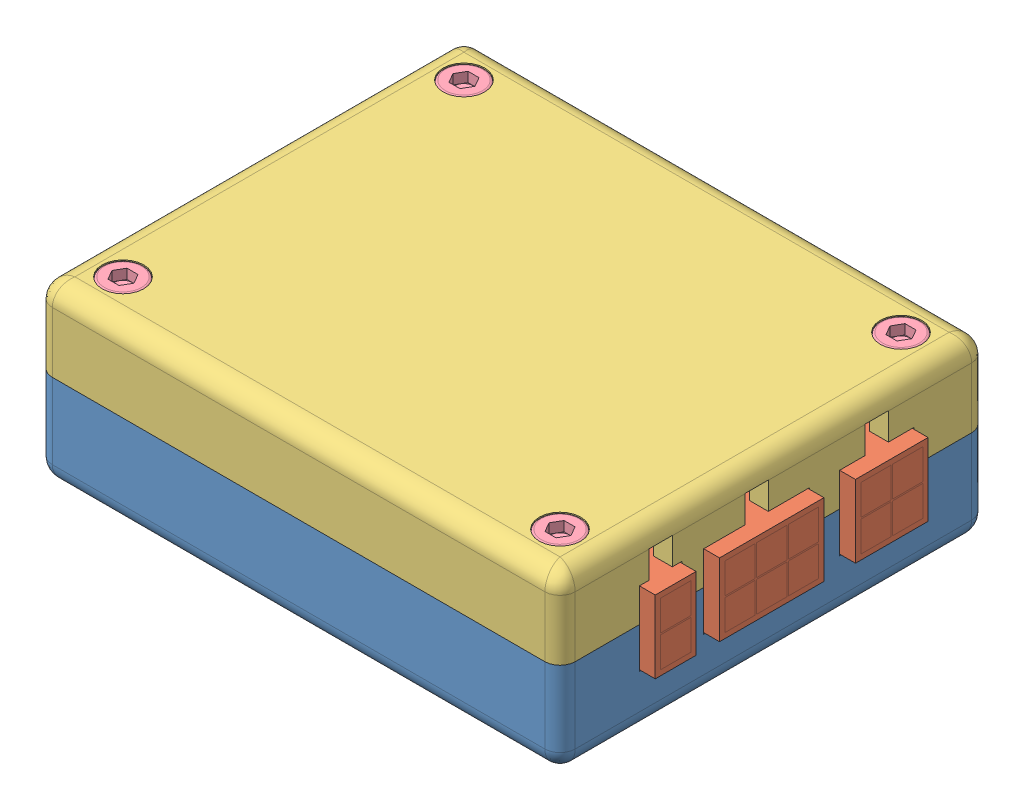
SolidWorks assembly Housing, configuration Standard. Lengths in mm.
Overall size (73.14 23 56.44).
11 component instances, 5 part files, 29 mates.
Components (placement in the parent):
- Housing-Bottom-1: Housing-Bottom [Standard] at (-69.135 0 56.435) size (69.14 12.5 56.44)
- Audio-Switch-1: Audio-Switch [Standard] at (-66.635 6.3 53.935) x (1 0 0) z (0 1 0) size (73.14 51.44 13.69)
- Housing-Top-1: Housing-Top [Standard] at (-69.135 20.5 56.435) size (69.14 15.9 56.44)
- socket head cap screw_din-1: socket head cap screw_din [DIN 912 M3 x 20 --- 20S] at (-5.675 23 50.76) x (0 -1 0) z (0 0 1) size (23 5.5 5.5)
- socket head cap screw_din-2: socket head cap screw_din [DIN 912 M3 x 20 --- 20S] at (-63.46 23 5.675) x (0 -1 0) z (0 0 1) size (23 5.5 5.5)
- socket head cap screw_din-3: socket head cap screw_din [DIN 912 M3 x 20 --- 20S] at (-63.46 23 50.76) x (0 -1 0) z (0 0 1) size (23 5.5 5.5)
- socket head cap screw_din-4: socket head cap screw_din [DIN 912 M3 x 20 --- 20S] at (-5.675 23 5.675) x (0 -1 0) z (0 0 1) size (23 5.5 5.5)
- hex thin nut chamfered gradeab_din-1: hex thin nut chamfered gradeab_din [Hexagon Thin Nut ISO 4035 - M3 - S] at (-63.46 2 50.76) x (1 0 0) z (0 1 0) size (5.5 6.35 1.8)
- hex thin nut chamfered gradeab_din-2: hex thin nut chamfered gradeab_din [Hexagon Thin Nut ISO 4035 - M3 - S] at (-63.46 2 5.675) x (1 0 0) z (0 1 0) size (5.5 6.35 1.8)
- hex thin nut chamfered gradeab_din-3: hex thin nut chamfered gradeab_din [Hexagon Thin Nut ISO 4035 - M3 - S] at (-5.675 2 5.675) x (1 0 0) z (0 1 0) size (5.5 6.35 1.8)
- hex thin nut chamfered gradeab_din-4: hex thin nut chamfered gradeab_din [Hexagon Thin Nut ISO 4035 - M3 - S] at (-5.675 2 50.76) x (1 0 0) z (0 1 0) size (5.5 6.35 1.8)
Mates (geometry in assembly coordinates):
- Deckungsgleich2: coincident anti-aligned: plane of Housing-Bottom-1 through (-66.635 12.5 53.935) normal (0 0 -1); plane of Audio-Switch-1 through (-2.5 5.5 53.935) normal (0 0 1)
- Deckungsgleich3: coincident anti-aligned: plane of Housing-Bottom-1 through (-66.635 12.5 53.935) normal (1 0 0); plane of Audio-Switch-1 through (-66.635 5.5 53.935) normal (-1 0 0)
- Deckungsgleich4: coincident anti-aligned: plane of Housing-Bottom-1 through (-63.46 5.5 50.76) normal (0 1 0); plane of Audio-Switch-1 through (-66.635 5.5 53.935) normal (0 -1 0)
- Deckungsgleich5: coincident anti-aligned: plane of Housing-Bottom-1 through (-67.135 12.5 2) normal (0 1 0); plane of Housing-Top-1 through (-69.135 12.5 56.435) normal (0 -1 0)
- Deckungsgleich6: coincident aligned: plane of Housing-Bottom-1 through (-69.135 2.5 54.435) normal (-1 0 0); plane of Housing-Top-1 through (-69.135 23 54.435) normal (-1 0 0)
- Deckungsgleich7: coincident aligned: plane of Housing-Bottom-1 through (-67.135 2.5 56.435) normal (0 0 1); plane of Housing-Top-1 through (-67.135 23 56.435) normal (0 0 1)
- Deckungsgleich8: coincident anti-aligned: plane of Housing-Top-1 through (-63.46 20 5.675) normal (0 1 0); plane of socket head cap screw_din-2 through (-60.71 20 5.675) normal (0 -1 0)
- Deckungsgleich9: coincident anti-aligned: plane of Housing-Top-1 through (-63.46 20 50.76) normal (0 1 0); plane of socket head cap screw_din-3 through (-60.71 20 50.76) normal (0 -1 0)
- Deckungsgleich10: coincident anti-aligned: plane of Housing-Top-1 through (-5.675 20 5.675) normal (0 1 0); plane of socket head cap screw_din-4 through (-2.925 20 5.675) normal (0 -1 0)
- Deckungsgleich11: coincident anti-aligned: plane of Housing-Top-1 through (-5.675 20 50.76) normal (0 1 0); plane of socket head cap screw_din-1 through (-2.925 20 50.76) normal (0 -1 0)
- Konzentrisch1: concentric anti-aligned: cylinder of Housing-Top-1 through (-63.46 23 5.675) axis (0 -1 0) radius 1.5; cylinder of socket head cap screw_din-2 through (-63.46 54.75 5.675) axis (0 1 0) radius 1.5
- Konzentrisch2: concentric anti-aligned: cylinder of Housing-Top-1 through (-63.46 23 50.76) axis (0 -1 0) radius 1.5; cylinder of socket head cap screw_din-3 through (-63.46 54.75 50.76) axis (0 1 0) radius 1.5
- Konzentrisch3: concentric anti-aligned: cylinder of Housing-Top-1 through (-5.675 23 5.675) axis (0 -1 0) radius 1.5; cylinder of socket head cap screw_din-4 through (-5.675 54.75 5.675) axis (0 1 0) radius 1.5
- Konzentrisch4: concentric anti-aligned: cylinder of Housing-Top-1 through (-5.675 23 50.76) axis (0 -1 0) radius 1.5; cylinder of socket head cap screw_din-1 through (-5.675 54.75 50.76) axis (0 1 0) radius 1.5
- Deckungsgleich12: coincident anti-aligned: plane of Housing-Bottom-1 through (-69.135 2 56.435) normal (0 -1 0); plane of hex thin nut chamfered gradeab_din-4 through (-5.675 2 47.5846) normal (0 1 0)
- Deckungsgleich13: coincident anti-aligned: plane of Housing-Bottom-1 through (-69.135 2 56.435) normal (0 -1 0); plane of hex thin nut chamfered gradeab_din-3 through (-5.675 2 2.4996) normal (0 1 0)
- Deckungsgleich15: coincident anti-aligned: plane of Housing-Bottom-1 through (-69.135 2 56.435) normal (0 -1 0); plane of hex thin nut chamfered gradeab_din-1 through (-63.46 2 47.5846) normal (0 1 0)
- Deckungsgleich16: coincident anti-aligned: plane of Housing-Bottom-1 through (-69.135 2 56.435) normal (0 -1 0); plane of hex thin nut chamfered gradeab_din-2 through (-63.46 2 2.4996) normal (0 1 0)
- Deckungsgleich17: coincident anti-aligned: plane of Housing-Bottom-1 through (-2.925 2 49.1723) normal (-1 0 0); plane of hex thin nut chamfered gradeab_din-4 through (-2.925 0.2 49.1723) normal (1 0 0)
- Deckungsgleich18: coincident anti-aligned: plane of Housing-Bottom-1 through (-2.925 2 52.3477) normal (-0.5 0 -0.866025); plane of hex thin nut chamfered gradeab_din-4 through (-5.675 0.2 53.9354) normal (0.5 0 0.866025)
- Deckungsgleich19: coincident anti-aligned: plane of Housing-Bottom-1 through (-5.675 2 2.4996) normal (-0.5 0 0.866025); plane of hex thin nut chamfered gradeab_din-3 through (-2.925 0.2 4.0873) normal (0.5 0 -0.866025)
- Deckungsgleich20: coincident anti-aligned: plane of Housing-Bottom-1 through (-8.425 2 4.0873) normal (0.5 0 0.866025); plane of hex thin nut chamfered gradeab_din-3 through (-5.675 0.2 2.4996) normal (-0.5 0 -0.866025)
- Deckungsgleich21: coincident anti-aligned: plane of Housing-Bottom-1 through (-63.46 2 47.5846) normal (-0.5 0 0.866025); plane of hex thin nut chamfered gradeab_din-1 through (-60.71 0.2 49.1723) normal (0.5 0 -0.866025)
- Deckungsgleich22: coincident anti-aligned: plane of Housing-Bottom-1 through (-60.71 2 49.1723) normal (-1 0 0); plane of hex thin nut chamfered gradeab_din-1 through (-60.71 0.2 49.1723) normal (1 0 0)
- Deckungsgleich23: coincident anti-aligned: plane of Housing-Bottom-1 through (-60.71 2 7.2627) normal (-0.5 0 -0.866025); plane of hex thin nut chamfered gradeab_din-2 through (-63.46 0.2 8.8504) normal (0.5 0 0.866025)
- Deckungsgleich24: coincident anti-aligned: plane of Housing-Bottom-1 through (-60.71 2 4.0873) normal (-1 0 0); plane of hex thin nut chamfered gradeab_din-2 through (-60.71 0.2 4.0873) normal (1 0 0)
- Deckungsgleich25: coincident anti-aligned: plane of Housing-Bottom-1 through (-2 0 54.435) normal (0 -1 0); plane of assembly through (0 0 0) normal (0 1 0)
- Deckungsgleich26: coincident anti-aligned: plane of Housing-Bottom-1 through (-67.135 2.5 0) normal (0 0 -1); plane of assembly through (0 0 0) normal (0 0 1)
- Deckungsgleich27: coincident aligned: plane of Housing-Bottom-1 through (0 2.5 54.435) normal (1 0 0); plane of assembly through (0 0 0) normal (1 0 0)
